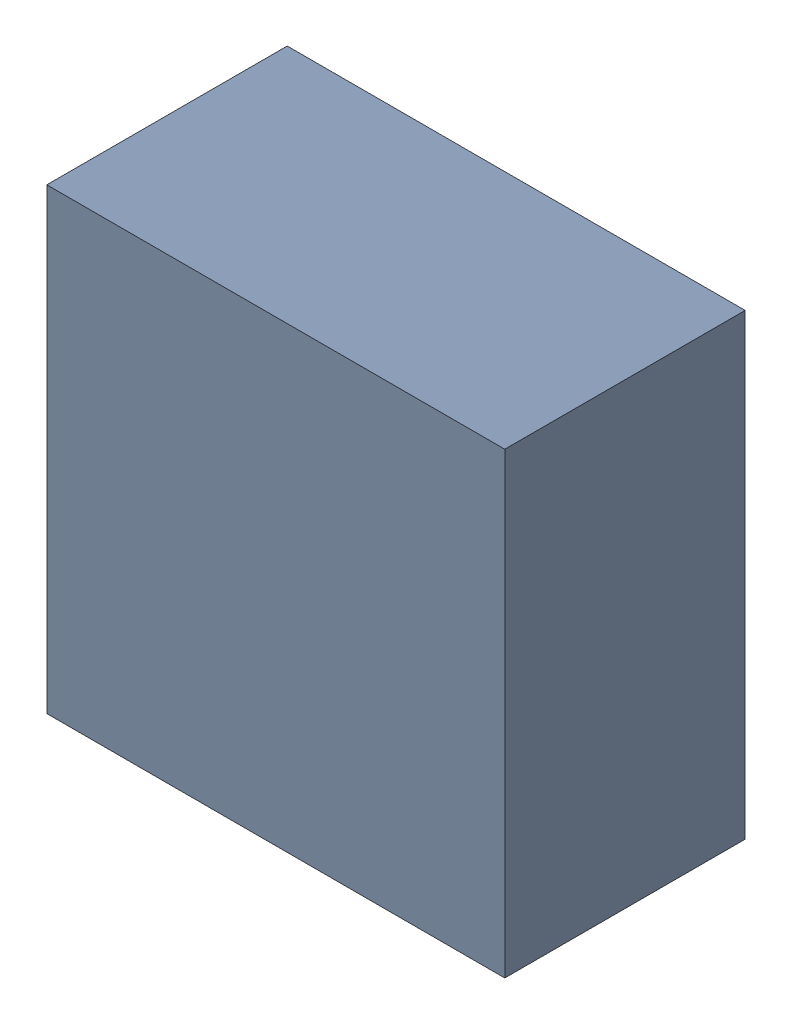
SolidWorks assembly L15, configuration Default. Lengths in mm.
Overall size (4 4 2.1).
2 component instances, 1 part files, 0 mates.
Components (placement in the parent):
- 836756080-1: 836756080 [Default] at (109.95 58.55 0) size (4 4 2.1)
  - Extruded_40-1: Extruded_40 [Default] at origin size (4 4 2.1)
